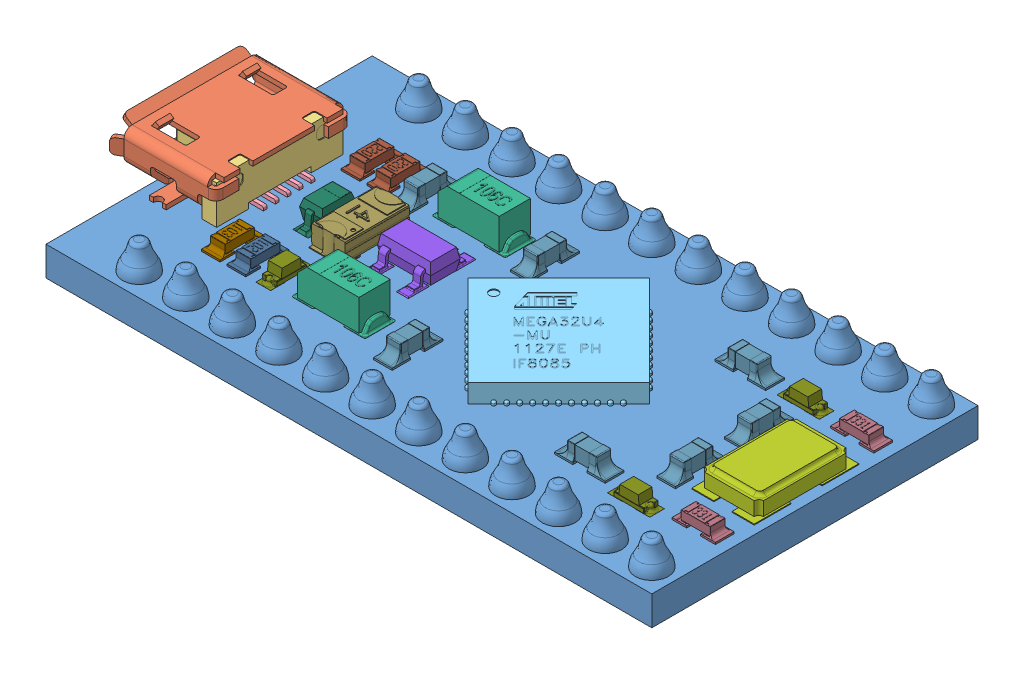
SolidWorks assembly ARDUINO PRO MICRO, configuration Default. Lengths in mm.
Overall size (34.59 4.27 20.13).
34 component instances, 16 part files, 0 mates.
Components (placement in the parent):
- micro board-1: micro board [Default] at origin size (33.02 3.1 17.78)
- MICRO_stackable header 12-1: MICRO_stackable header 12 [Default] at (0 -3.9 0) (suppressed, hidden)
- micro usb-1: micro usb [Default] at (-4.75 1.85 -7.62) x (0 0 1) z (-1 0 0) size (8.01 3.25 5.93)
  - micro usb shell-1: micro usb shell [Default] at origin size (8.01 2.95 5.63)
  - micro usb internal-1: micro usb internal [Default] at (0 -0.25 0) size (6.9 2.9 4)
  - micro usb contact-1: micro usb contact [Default] at (1.3 -0.25 -0.1) size (0.2 1.3 4.4)
  - micro usb contact-2: micro usb contact [Default] at (0.65 -0.25 -0.1) size (0.2 1.3 4.4)
  - micro usb contact-3: micro usb contact [Default] at (0 -0.25 -0.1) size (0.2 1.3 4.4)
  - micro usb contact-4: micro usb contact [Default] at (-0.65 -0.25 -0.1) size (0.2 1.3 4.4)
  - micro usb contact-5: micro usb contact [Default] at (-1.3 -0.25 -0.1) size (0.2 1.3 4.4)
- atmega32U4-1: atmega32U4 [Default] at (15.24 1.62 -7.62) x (-0.707107 0 0.707107) z (-0.707107 0 -0.707107) size (7.23 1.03 7.23)
- MICRO_cap106C-1: MICRO_cap106C [Default] at (7.3558 1.6 -11.4427) x (0 0 -1) z (1 0 0) size (1.7 1.81 4)
- MICRO_cap106C-2: MICRO_cap106C [Default] at (7.3558 1.6 -3.7973) x (0 0 -1) z (1 0 0) size (1.7 1.81 4)
- MICRO_stackable header 12-2: MICRO_stackable header 12 [Default] at (0 -3.9 -15.24) (suppressed, hidden)
- micro_crystal 5x3-1: micro_crystal 5x3 [Default] at (27.051 1.65 -7.62) x (0 0 -1) z (1 0 0) size (5.7 1 3.4)
- micro_MIC5219-1: micro_MIC5219 [Default] at (7.366 1.6 -7.874) x (-1 0 0) z (0 0 -1) size (2.9 1.2 3.68)
- MICRO_603 resistor 103-1: MICRO_603 resistor 103 [Default] at (1.27 1.6 -3.81) x (0 0 1) z (-1 0 0) size (2.36 0.62 1.04)
- MICRO_603 resistor 102-1: MICRO_603 resistor 102 [Default] at (2.667 1.6 -3.81) x (0 0 1) z (-1 0 0) size (2.36 0.62 1.04)
- MICRO_603 resistor 22-1: MICRO_603 resistor 22 [Default] at (1.27 1.6 -11.43) x (0 0 1) z (-1 0 0) size (2.36 0.62 1.04)
- MICRO_603 resistor 22-2: MICRO_603 resistor 22 [Default] at (2.667 1.6 -11.43) x (0 0 1) z (-1 0 0) size (2.36 0.62 1.04)
- MICRO_PTC-1206-1: MICRO_PTC-1206 [Default] at (4.445 1.6 -7.62) x (0 0 1) z (-1 0 0) size (3.85 1.19 1.82)
- MICRO_603 resistor 331-1: MICRO_603 resistor 331 [Default] at (27.432 1.6 -11.938) size (2.36 0.62 1.04)
- MICRO_603 resistor 331-2: MICRO_603 resistor 331 [Default] at (27.432 1.6 -3.302) size (2.36 0.62 1.04)
- MICRO_603 cap on pad-1: MICRO_603 cap on pad [Default] at (24.384 1.6 -9.398) x (0 0 1) z (-1 0 0) size (2.76 0.9 1.02)
- MICRO_603 cap on pad-2: MICRO_603 cap on pad [Default] at (21.336 1.6 -11.938) size (2.76 0.9 1.02)
- MICRO_603 cap on pad-3: MICRO_603 cap on pad [Default] at (24.384 1.6 -5.715) x (0 0 1) z (-1 0 0) size (2.76 0.9 1.02)
- MICRO_603 cap on pad-4: MICRO_603 cap on pad [Default] at (21.336 1.6 -3.1877) size (2.76 0.9 1.02)
- MICRO_603 cap on pad-5: MICRO_603 cap on pad [Default] at (11.0744 1.6 -3.5839) x (0 0 -1) z (1 0 0) size (2.76 0.9 1.02)
- MICRO_603 cap on pad-6: MICRO_603 cap on pad [Default] at (10.6528 1.6 -11.4681) x (0 0 1) z (-1 0 0) size (2.76 0.9 1.02)
- MICRO_603 cap on pad-7: MICRO_603 cap on pad [Default] at (4.1758 1.6 -11.43) x (0 0 -1) z (1 0 0) size (2.76 0.9 1.02)
- SOD 323-1: SOD 323 [Default] at (2.6416 1.6 -7.62) x (0 0 1) z (-1 0 0) size (2.96 1.11 1.25)
- MICRO_led-1: MICRO_led [Default] at (24.384 1.62 -2.6907) size (2.3 0.72 0.8)
- MICRO_led-2: MICRO_led [Default] at (24.384 1.62 -11.938) size (2.3 0.72 0.8)
- MICRO_led-3: MICRO_led [Default] at (4.1046 1.62 -3.81) x (0 0 -1) z (1 0 0) size (2.3 0.72 0.8)
